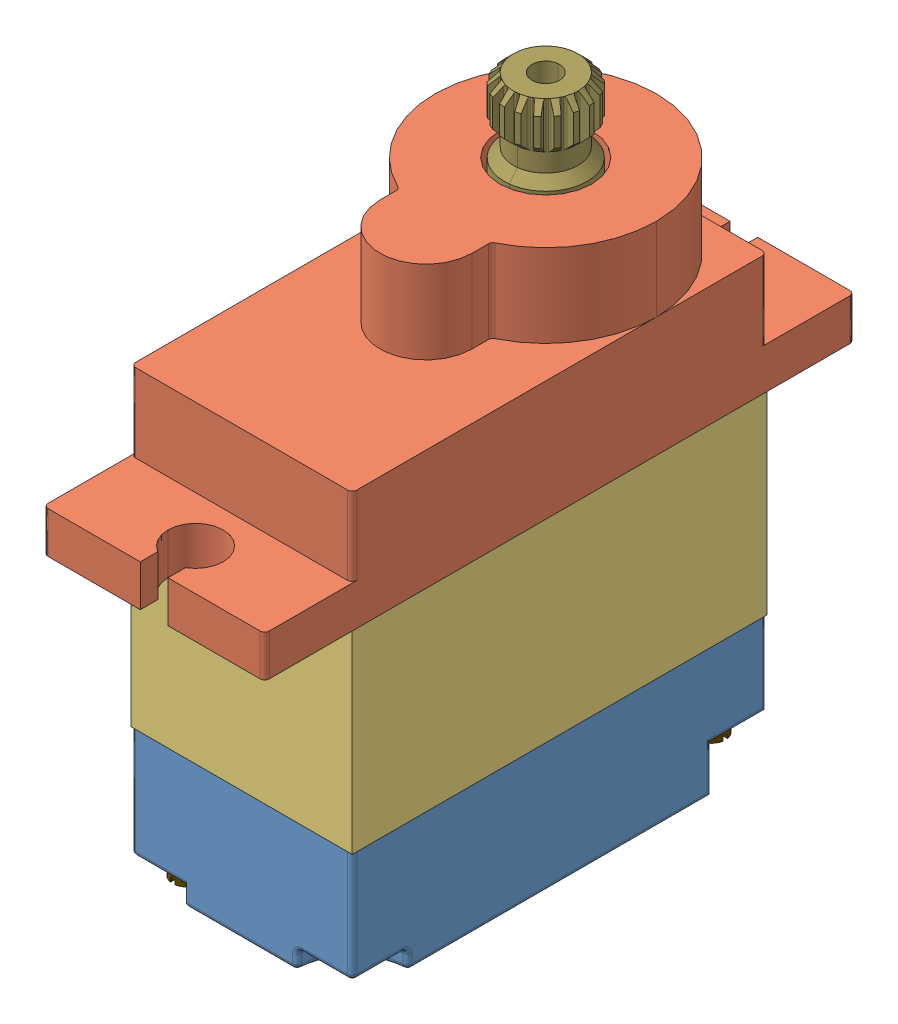
SolidWorks assembly MG90S, configuration Default. Lengths in mm.
Overall size (13.58 32.57 32).
20 component instances, 18 part files, 0 mates.
Components (placement in the parent):
- MG90S.STEP-1: MG90S.STEP [Default] at origin size (13.58 32.57 32)
  - Part1.STEP-1: Part1.STEP [Default] at (21.0878 -43.0505 -32.5824) x (0 0 -1) z (1 0 0) size (22.54 9.07 12)
  - Part2.STEP-1: Part2.STEP [Default] at (21.0878 -25.5505 -32.5824) x (0 0 -1) z (1 0 0) size (32 13 12)
  - Part3.STEP-1: Part3.STEP [Default] at (21.0878 -36.0505 -32.5824) x (0 0 -1) z (1 0 0) size (22.5 16 12)
  - spur gear_iso_ISO - Spur gear 0.25M 38T 20PA 1.5FW ---S38A75H50L1.5N.STEP-1: spur gear_iso_ISO - Spur gear 0.25M 38T 20PA 1.5FW ---S38A75H50L1.5N.STEP [Default] at (21.0878 -22.3005 -37.8324) x (0 -1 0) z (0.87496 0 0.484196) size (1.5 9.98 10)
  - spur gear_iso_ISO - Spur gear 0.3M 31T 20PA 2FW ---S31A75H50L1.25N.STEP-1: spur gear_iso_ISO - Spur gear 0.3M 31T 20PA 2FW ---S31A75H50L1.25N.STEP [Default] at (21.0878 -19.8005 -31.3324) x (0 -1 0) z (0.109568 0 -0.993979) size (2 9.88 9.89)
  - spur gear_iso_ISO - Spur gear 0.4M 23T 20PA 2.75FW ---S23A75H50L1.5N.STEP-1: spur gear_iso_ISO - Spur gear 0.4M 23T 20PA 2.75FW ---S23A75H50L1.5N.STEP [Default] at (21.0878 -19.8005 -37.8324) x (0 1 0) z (-0.993238 0 0.116099) size (2.75 9.97 9.99)
  - spur gear_iso_ISO - Spur gear 0.25M 31T 20PA 1.25FW ---S31A75H50L1.25N.STEP-1: spur gear_iso_ISO - Spur gear 0.25M 31T 20PA 1.25FW ---S31A75H50L1.25N.STEP [Default] at (21.0878 -25.0505 -31.3324) x (0 1 0) z (0.977188 0 0.212376) size (1.25 8.24 8.25)
  - spur gear_iso_ISO - Spur gear 0.25M 10T 20PA 2FW ---S10A75H50L1.25N.STEP-1: spur gear_iso_ISO - Spur gear 0.25M 10T 20PA 2FW ---S10A75H50L1.25N.STEP [Default] at (21.0878 -23.8005 -31.3324) x (0 1 0) z (0.977188 0 0.212376) size (2 2.87 3)
  - gear3.STEP-1: gear3.STEP [Default] at (21.0878 -22.3005 -37.8324) x (0.87496 0 0.484196) z (-0.484196 0 0.87496) size (3.98 2.5 3.92)
  - gear1.STEP-1: gear1.STEP [Default] at (21.0878 -19.8005 -31.3324) x (0.109568 0 -0.993979) z (0.993979 0 0.109568) size (3.96 2.5 3.87)
  - gear2.STEP-1: gear2.STEP [Default] at (21.0878 -26.3005 -26.3324) x (0.891105 0 -0.453797) z (0.453797 0 0.891105) size (2.5 2.5 2.5)
  - Part4.STEP-1: Part4.STEP [Default] at (21.0878 -17.0505 -37.8324) x (0.993238 0 -0.116099) z (0.116099 0 0.993238) size (4.5 6.5 4.5)
  - Motor_Body.STEP-1: Motor_Body.STEP [Default] at (21.0878 -26.5505 -26.3324) x (-1 0 0) z (0 0 1) size (10 14.25 8)
  - Motor_Body2.STEP-1: Motor_Body2.STEP [Default] at (21.0878 -39.0505 -26.3324) size (10 2 8)
  - cilinder2.STEP-1: cilinder2.STEP [Default] at (21.0878 -31.8005 -37.8324) x (0.116099 0 0.993238) z (-0.993238 0 0.116099) size (1.5 15 1.5)
  - cilinder1.STEP-1: cilinder1.STEP [Default] at (21.0878 -27.3005 -31.3324) x (0.109568 0 -0.993979) z (0.993979 0 0.109568) size (1.25 12 1.25)
  - Part5.STEP-1: Part5.STEP [Default] at (21.0878 -40.0505 -32.0824) x (0 0 -1) z (1 0 0) size (19.28 16 10.15)
  - Part6.STEP-1: Part6.STEP [Default] at (16.5878 -42.0505 -22.8324) size (1.5 21 1.5)
  - Part6.STEP-2: Part6.STEP [Default] at (25.5878 -40.5505 -42.3324) size (1.5 21 1.5)
